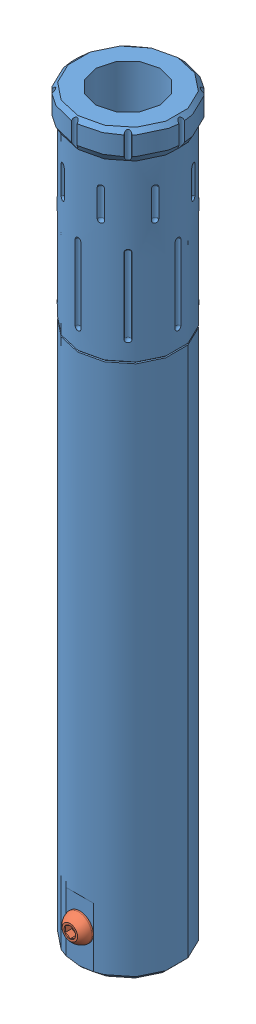
SolidWorks assembly body, configuration Default. Lengths in mm.
Overall size (14.1 96 14.67).
2 component instances, 2 part files, 3 mates.
Components (placement in the parent):
- body-1: body [Default] at origin size (14.1 96 14.1)
- 92095A110_BUTTON HEAD HEX DRIVE SCREW-1: 92095A110_BUTTON HEAD HEX DRIVE SCREW [92095A110] at (0 4.7 7.55) size (3.5 3.5 3.5)
Mates (geometry in assembly coordinates):
- Coincident1: coordinate: point of body-1
- Concentric1: concentric aligned: cylinder of body-1 through (0 4.7 6.25) axis (0 0 1) radius 0.8; cylinder of 92095A110_BUTTON HEAD HEX DRIVE SCREW-1 through (0 4.7 7.55) axis (0 0 1) radius 1.75
- Coincident2: coincident anti-aligned: plane of body-1 through (-7.0495 0 6.25) normal (0 0 1); plane of 92095A110_BUTTON HEAD HEX DRIVE SCREW-1 through (0 2.95 6.25) normal (0 0 -1)
